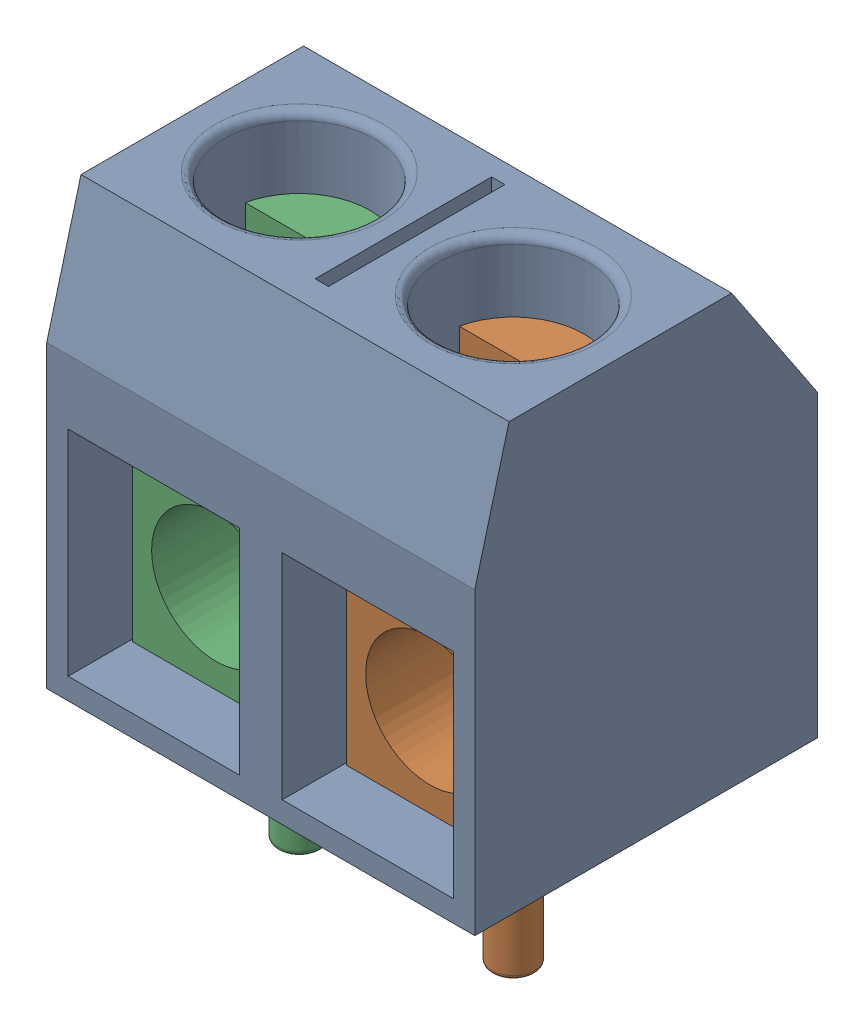
SolidWorks assembly TB2, configuration Default. Lengths in mm.
Overall size (10 13.5 8).
3 component instances, 2 part files, 0 mates.
Components (placement in the parent):
- User_Library-TB2_TB_case_1-1: User_Library-TB2_TB_case_1 [Default] at (-10 0 0) x (0 0 1) z (0 1 0) size (8 10 10)
- User_Library-TB2_TB_screw_1-1: User_Library-TB2_TB_screw_1 [Default] at (-2.5 -4.6 4.6) x (-1 0 0) z (0 0 -1) size (3.9 11.9 3.9)
- User_Library-TB2_TB_screw_1-2: User_Library-TB2_TB_screw_1 [Default] at (-7.5 -4.6 4.6) size (3.9 11.9 3.9)
